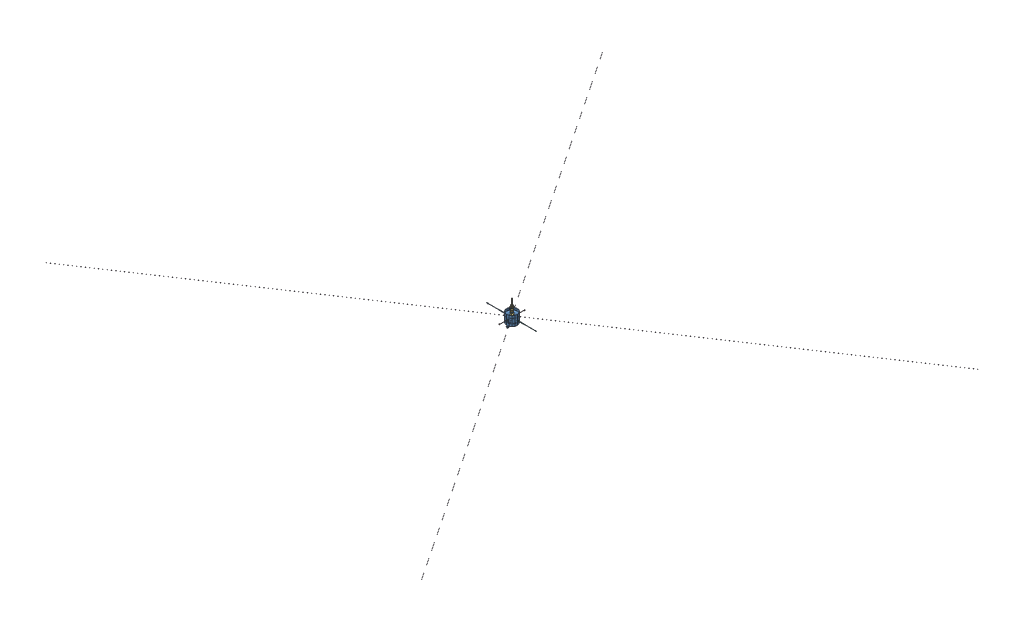
SolidWorks assembly isee3, configuration Default. Lengths in mm.
Overall size (92822.76 10739.79 92822.76).
22 component instances, 7 part files, 31 mates.
Components (placement in the parent):
- Core2-1: Core2 [Default] at (-1.237 -643.1887 -5.3376) size (1767.46 1848.59 2075.51)
- Inertiaboom-1: Inertiaboom [Default] at (-1.237 94.9613 874.6624) size (80 200 1241.6)
- Inertiaboom-2: Inertiaboom [Default] at (-1.237 94.9613 -885.3376) x (-1 0 0) z (0 0 -1) size (80 200 1241.6)
- zantenna-1: zantenna [Default] at (-1.237 538.7113 -5.3376) x (-0.896873 0 -0.442289) z (0.442289 0 -0.896873) size (550 9285.6 550)
- radantenna-1: radantenna [Default] at (-31067.7537 279.1586 -46413.6699) x (0.085807 -0.994661 -0.057335) z (0.55557 0 0.83147) size (10 10 55000)
- radantenna-2: radantenna [Default] at (46407.0953 279.1586 -31071.8544) x (0.057335 -0.994661 0.085807) z (-0.83147 0 0.55557) size (10 10 55000)
- radantenna-3: radantenna [Default] at (31065.2798 279.1586 46402.9947) x (-0.085807 -0.994661 0.057335) z (-0.55557 0 -0.83147) size (10 10 55000)
- radantenna-4: radantenna [Default] at (-46409.5693 279.1586 31061.1791) x (-0.057335 -0.994661 -0.085807) z (0.83147 0 -0.55557) size (10 10 55000)
- Exboom1-1: Exboom1 [Default] at (-881.237 94.9613 -5.3376) x (0 0 1) z (-1 0 0) size (270 205.29 3372.2)
- Exboom2-1: Exboom2 [Default] at (878.763 94.9613 -5.3376) x (0 0 -1) z (1 0 0) size (120 100 3142.2)
- thruster-1: thruster [Default] at (-1.9019 -643.0482 -8.6803) x (0.19509 0 0.980785) z (-0.980785 0 0.19509) size (91.83 130.56 47.16)
- thruster-2: thruster [Default] at (239.2525 231.989 891.3763) x (0 -1 0) z (0.19509 0 0.980785) size (91.83 130.56 47.16)
- thruster-3: thruster [Default] at (119.7374 231.989 915.1498) x (0 -1 0) z (-0.19509 0 -0.980785) size (91.83 130.56 47.16)
- thruster-4: thruster [Default] at (1095.8735 -22.7019 586.9582) x (-0.980785 0 0.19509) z (0 -1 0) size (91.83 130.56 47.16)
- thruster-5: thruster [Default] at (1148.3505 250.8378 575.817) x (-0.980785 0 0.19509) z (0 -1 0) size (91.83 130.56 47.16)
- thruster-6: thruster [Default] at (-31.1432 763.0687 119.8112) x (0.147249 -0.655984 0.740272) z (0.980785 0 -0.19509) size (91.83 130.56 47.16)
- thruster-7: thruster [Default] at (-122.2113 231.989 -925.8251) x (0 -1 0) z (0.19509 0 0.980785) size (91.83 130.56 47.16)
- thruster-8: thruster [Default] at (28.6692 763.0687 -130.4865) x (-0.147249 -0.655984 -0.740272) z (-0.980785 0 0.19509) size (91.83 130.56 47.16)
- thruster-9: thruster [Default] at (-1150.8244 250.8378 -586.4922) x (0.980785 0 -0.19509) z (0 -1 0) size (91.83 130.56 47.16)
- thruster-10: thruster [Default] at (-1098.3475 -22.7019 -597.6334) x (0.980785 0 -0.19509) z (0 -1 0) size (91.83 130.56 47.16)
- thruster-11: thruster [Default] at (-241.7264 231.989 -902.0515) x (0 -1 0) z (-0.19509 0 -0.980785) size (91.83 130.56 47.16)
- thruster-12: thruster [Default] at (-0.5721 -643.0482 -1.995) x (-0.19509 0 -0.980785) z (0.980785 0 -0.19509) size (91.83 130.56 47.16)
Mates (geometry in assembly coordinates):
- Coincident1: coincident: plane of Core2-1 through (-1.237 -643.1887 874.6624) normal (0 0 1); plane of Inertiaboom-1 through (-1.237 94.9613 874.6624) normal (0 0 -1)
- Coincident2: coincident: line of Core2-1 through (38.763 124.9613 874.6624) axis (-1 0 0); line of Inertiaboom-1 through (38.763 124.9613 874.6624) axis (-1 0 0)
- Coincident3: coincident: line of Core2-1 through (-41.237 124.9613 874.6624) axis (0 -1 0); line of Inertiaboom-1 through (-41.237 124.9613 874.6624) axis (0 -1 0)
- Coincident4: coincident: plane of Core2-1 through (-1.237 538.7113 -5.3376) normal (0 1 0); plane of zantenna-1 through (-1.237 538.7113 -5.3376) normal (0 -1 0)
- Coincident5: coincident: line of Core2-1 through (-1.237 1011.9263 -5.3376) axis (0 -1 0); line of zantenna-1 through (-1.237 2026.5613 -5.3376) axis (0 -1 0)
- Concentric1: concentric: cylinder of Core2-1 through (-511.3909 279.1586 -682.8412) axis (-0.55557 0 -0.83147) radius 10; cylinder of radantenna-1 through (-511.3909 279.1586 -682.8412) axis (-0.55557 0 -0.83147) radius 5
- Coincident7: coincident: plane of Core2-1 through (-511.3909 279.1586 -682.8412) normal (-0.55557 0 -0.83147); plane of radantenna-1 through (-511.3909 279.1586 -682.8412) normal (0.55557 0 0.83147)
- Coincident8: coincident: plane of Core2-1 through (-881.237 -643.1887 -5.3376) normal (-1 0 0); plane of Exboom1-1 through (-881.237 94.9613 -5.3376) normal (1 0 0)
- Coincident9: coincident: line of Core2-1 through (-881.237 124.9613 54.6624) axis (0 0 -1); line of Exboom1-1 through (-881.237 124.9613 54.6624) axis (0 0 -1)
- Coincident10: coincident: line of Core2-1 through (-881.237 124.9613 -65.3376) axis (0 -1 0); line of Exboom1-1 through (-881.237 124.9613 -65.3376) axis (0 -1 0)
- Coincident11: coincident: plane of Core2-1 through (878.763 -643.1887 -5.3376) normal (1 0 0); plane of Exboom2-1 through (878.763 94.9613 -5.3376) normal (-1 0 0)
- Coincident12: coincident: line of Core2-1 through (878.763 124.9613 -65.3376) axis (0 0 1); line of Exboom2-1 through (878.763 124.9613 -65.3376) axis (0 0 1)
- Coincident13: coincident: line of Core2-1 through (878.763 124.9613 54.6624) axis (0 -1 0); line of Exboom2-1 through (878.763 124.9613 54.6624) axis (0 -1 0)
- Parallel1: parallel: plane of Core2-1 through (-477.2218 -643.1887 -717.6992) normal (-0.55557 0 -0.83147); plane of zantenna-1 through (141.9279 1624.9133 -212.5004) normal (-0.55557 0 -0.83147)
- Coincident16: coincident: plane of Core2-1 through (-1.237 -643.1887 -5.3376) normal (-0.980785 0 0.19509); plane of thruster-1 through (-1.9019 -643.0482 -8.6803) normal (-0.980785 0 0.19509)
- Lock1: lock: unknown of Core2-1; unknown of thruster-1
- Parallel2: parallel: plane of thruster-2 through (-26.9273 -802.9746 944.3227) normal (-0.980785 0 0.19509); plane of Core2-1 through (44.4191 -231.4535 810.0732) normal (-0.980785 0 0.19509)
- Parallel3: parallel: plane of Core2-1 through (200.7498 -643.1887 1010.1184) normal (0.19509 0 0.980785); plane of thruster-2 through (239.2525 231.989 891.3763) normal (0.19509 0 0.980785)
- Lock2: lock: unknown of Core2-1; unknown of thruster-2
- Parallel6: parallel: plane of Core2-1 through (195.1429 -643.1887 981.9306) normal (0.19509 0 0.980785); plane of thruster-4 through (133.7429 -22.7019 1055.0493) normal (0.19509 0 0.980785)
- Coincident26: coincident: moEndPointRef_w of Core2-1; plane of thruster-4 through (1095.8735 -22.7019 586.9582) normal (0 -1 0)
- Parallel7: parallel: plane of Core2-1 through (117.1685 27.2981 997.4407) normal (0 1 0); plane of thruster-4 through (1095.8735 -22.7019 586.9582) normal (0 -1 0)
- Parallel8: parallel: plane of Core2-1 through (195.1429 -643.1887 981.9306) normal (0.19509 0 0.980785); plane of thruster-5 through (186.2199 250.8378 1043.9081) normal (0.19509 0 0.980785)
- Parallel9: parallel: plane of Core2-1 through (63.1096 300.8378 1008.1937) normal (0 1 0); plane of thruster-5 through (1148.3505 250.8378 575.817) normal (0 -1 0)
- Coincident31: coincident: moEndPointRef_w of Core2-1; plane of thruster-5 through (1148.3505 250.8378 575.817) normal (0 -1 0)
- Lock4: lock: unknown of Core2-1; unknown of thruster-5
- Parallel10: parallel: plane of Core2-1 through (138.5269 250.8378 972.8004) normal (0.19509 0 0.980785); plane of thruster-6 through (130.0526 250.8378 930.197) normal (-0.19509 0 -0.980785)
- Parallel11: parallel: plane of Core2-1 through (63.1096 300.8378 1008.1937) normal (-0.980785 0 0.19509); plane of thruster-6 through (-31.1432 763.0687 119.8112) normal (0.980785 0 -0.19509)
- Concentric2: concentric: cylinder of Core2-1 through (138.5269 250.8378 972.8004) axis (0.19509 0 0.980785) radius 20; cylinder of thruster-6 through (148.2503 250.8378 1021.6829) axis (0.19509 0 0.980785) radius 19.2957
- Lock5: lock: unknown of Core2-1; unknown of thruster-6
- Lock6: lock: unknown of Core2-1; unknown of thruster-4
